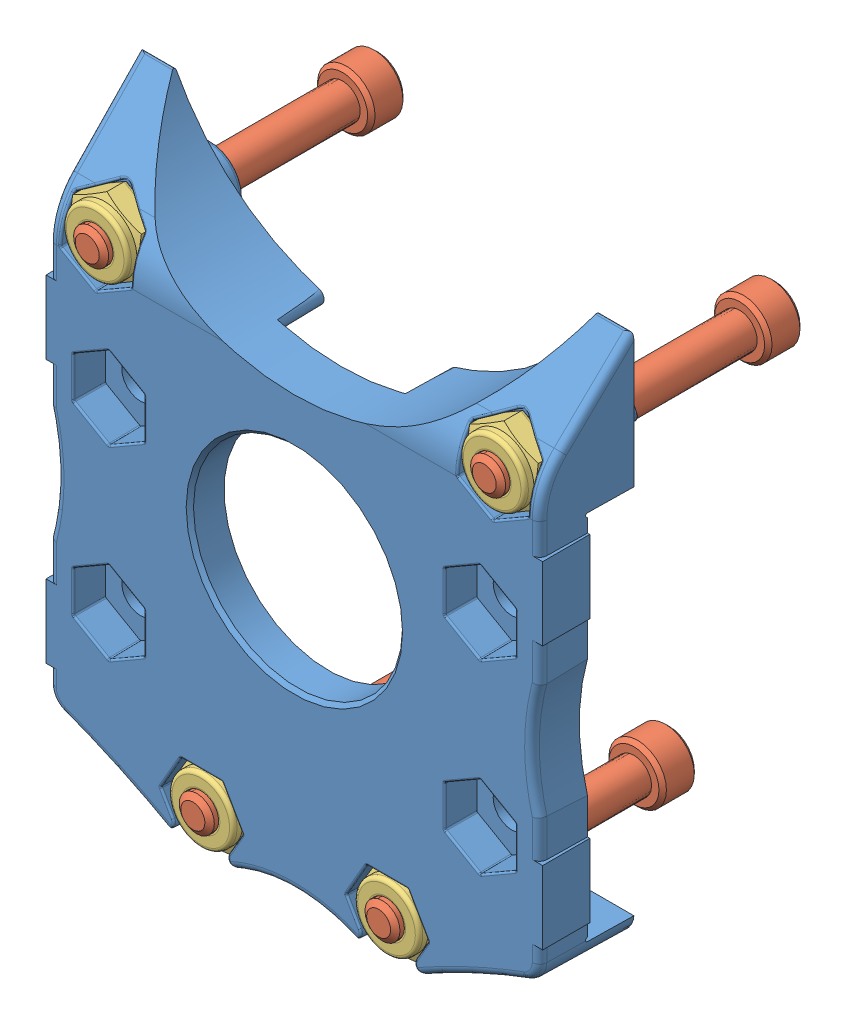
SolidWorks assembly Single Reduction Clamping Gearbox 217-4156, configuration Default. Lengths in mm.
Overall size (68.15 80.62 39.75).
10 component instances, 4 part files, 0 mates.
Components (placement in the parent):
- 217-4156-001 Rev6-1: 217-4156-001 Rev6 [Default] at origin (suppressed, hidden)
- 217-4156-002 Rev5-1: 217-4156-002 Rev5 [Default] at origin size (67.92 80.13 15.71)
- 217-4155-003 Rev1_SSA1032-1375ZB-1: 217-4155-003 Rev1_SSA1032-1375ZB [Default] at (-27.15 30.0962 -21.05) x (0.999179 -0.040505 0) z (0.040505 0.999179 0) size (7.87 39.75 7.87)
- 217-4155-003 Rev1_SSA1032-1375ZB-2: 217-4155-003 Rev1_SSA1032-1375ZB [Default] at (27.15 30.0962 -21.05) x (1 0 0) z (0 1 0) size (7.87 39.75 7.87)
- 217-4155-003 Rev1_SSA1032-1375ZB-3: 217-4155-003 Rev1_SSA1032-1375ZB [Default] at (12.7 -29.8538 -21.05) x (1 0 0) z (0 1 0) size (7.87 39.75 7.87)
- 217-4155-003 Rev1_SSA1032-1375ZB-4: 217-4155-003 Rev1_SSA1032-1375ZB [Default] at (-12.7 -29.8538 -21.05) x (1 0 0) z (0 1 0) size (7.87 39.75 7.87)
- 217-4155-002 Rev2_NNY1032-ZC-1: 217-4155-002 Rev2_NNY1032-ZC [Default] at (-27.15 30.0962 8.35) x (-0.5 0.866025 0) z (0 0 1) size (9.39 10.84 4.45)
- 217-4155-002 Rev2_NNY1032-ZC-2: 217-4155-002 Rev2_NNY1032-ZC [Default] at (27.15 30.0962 8.35) size (9.39 10.84 4.45)
- 217-4155-002 Rev2_NNY1032-ZC-3: 217-4155-002 Rev2_NNY1032-ZC [Default] at (-12.7 -29.8538 8.35) x (0.866025 -0.5 0) z (0 0 1) size (9.39 10.84 4.45)
- 217-4155-002 Rev2_NNY1032-ZC-4: 217-4155-002 Rev2_NNY1032-ZC [Default] at (12.7 -29.8538 8.35) x (0.866025 -0.5 0) z (0 0 1) size (9.39 10.84 4.45)
